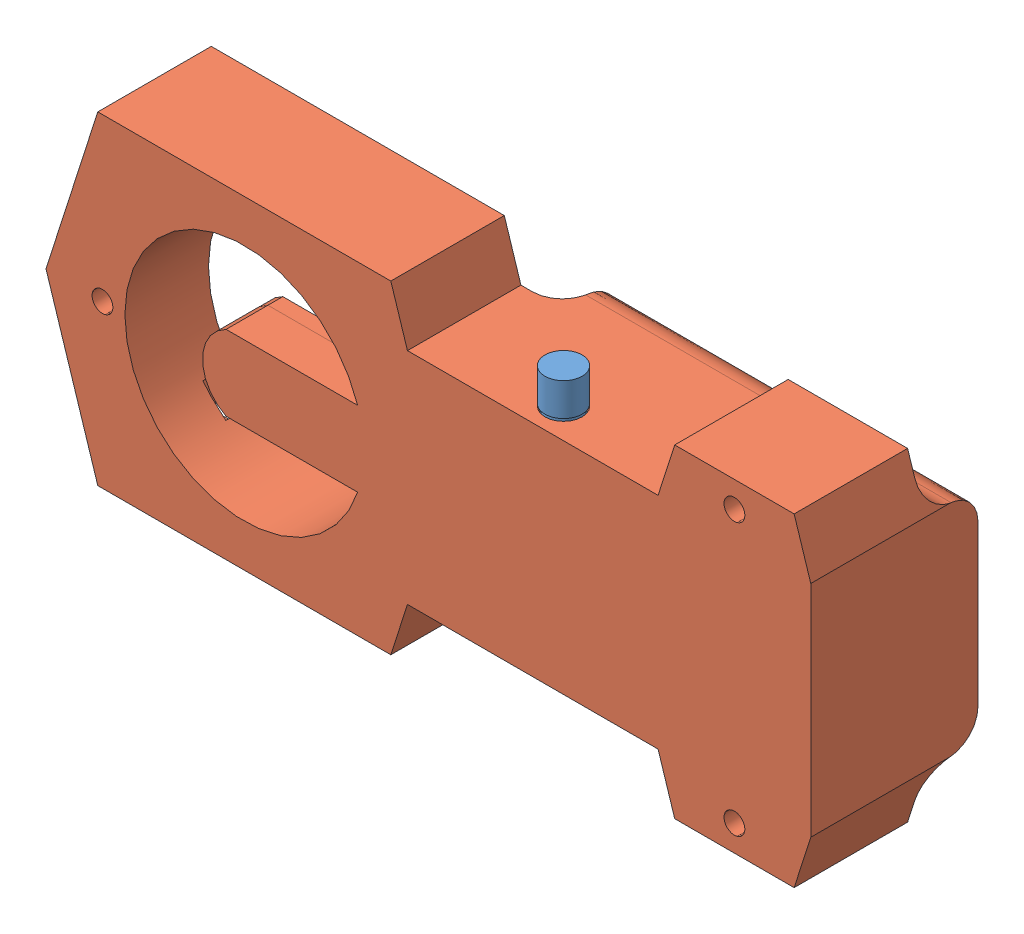
SolidWorks assembly sensor_asm, configuration Default. Lengths in mm.
Overall size (128.05 54.2 28).
6 component instances, 4 part files, 2 mates.
Components (placement in the parent):
- indicador-1: indicador [Default] at origin size (62 50 16) (hidden)
- pcb-1: pcb [Default] at (29.75 0 19) size (60 37.5 14.8)
- case_bat_r1-1: case_bat_r1 [Default] at origin size (128.05 54.2 28)
- battery_holder-1: battery_holder [Default] at (63.8862 0 14.3617) x (-1 0 0) z (0 0 -1) size (57 32.01 15)
- battery_holder-4: battery_holder [Default] at (47.8146 0 13.4476) x (0 -1 0) z (0 0 -1) size (57 32.01 15) (hidden)
- battery_holder-5: battery_holder [Default] at (61.9432 0 8.3992) x (0 -1 0) z (1 0 0) size (57 32.01 15) (hidden)
Mates (geometry in assembly coordinates):
- Concentric1: concentric: cylinder of indicador-1 through (23.75 0 16) axis (0 0 -1) radius 3.5; cylinder of pcb-1 through (23.75 0 20.6) axis (0 0 -1) radius 1.75
- Distance1: distance = 3 mm: plane of pcb-1 through (29.75 0 19) normal (0 0 -1); plane of indicador-1 through (0 0 16) normal (0 0 1)
